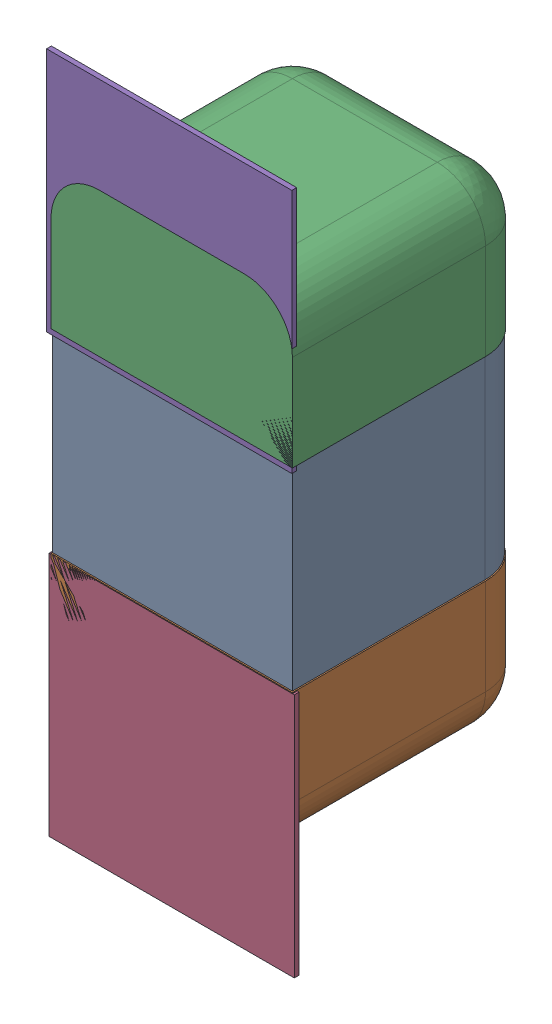
SolidWorks assembly C39, configuration Défaut. Lengths in mm.
Overall size (0.51 1.41 0.5).
8 component instances, 4 part files, 0 mates.
Components (placement in the parent):
- 6501210464-1: 6501210464 [Défaut] at (19.8374 -16.5918 -2.0818) x (0 1 0) z (-1 0 0) size (1 0.5 0.5)
  - Open CASCADE STEP translator 7.5 2.33.1.1-1: Open CASCADE STEP translator 7.5 2.33.1.1 [Défaut] at origin size (0.4 0.5 0.5)
  - Open CASCADE STEP translator 7.5 2.33.1.2-1: Open CASCADE STEP translator 7.5 2.33.1.2 [Défaut] at origin size (0.3 0.5 0.5)
  - Open CASCADE STEP translator 7.5 2.33.1.3-1: Open CASCADE STEP translator 7.5 2.33.1.3 [Défaut] at origin size (0.3 0.5 0.5)
- 6504207776-1: 6504207776 [Défaut] at (19.8374 -17.0491 -2.0918) size (0.51 0.51 0.01)
  - Extruded-1: Extruded [Défaut] at origin size (0.51 0.51 0.01)
- 6504207776-2: 6504207776 [Défaut] at (19.8322 -16.1468 -2.0918) size (0.51 0.51 0.01)
  - Extruded-1: Extruded [Défaut] at origin size (0.51 0.51 0.01)
